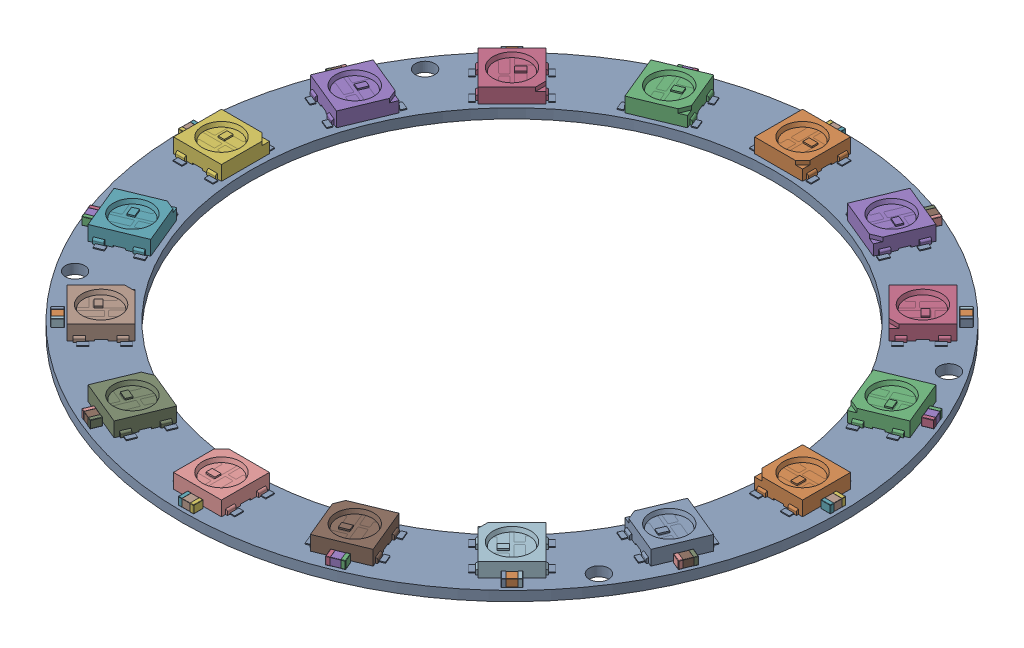
SolidWorks assembly ledRing, configuration Standard. Lengths in mm.
Overall size (68 2.5 68).
33 component instances, 3 part files, 6 mates.
Components (placement in the parent):
- LedRing-1: LedRing [Standard] at origin size (68 1.1 68)
- neopixel-1: neopixel [Standard] at (0 1 -29.975) x (0 0 1) z (0 1 0) size (4.95 5.35 1.7)
- neopixel-2: neopixel [Standard] at (-11.4709 1 -27.6933) x (0.382683 0 0.92388) z (0 1 0) size (4.95 5.35 1.7)
- neopixel-3: neopixel [Standard] at (-21.1955 1 -21.1955) x (0.707107 0 0.707107) z (0 1 0) size (4.95 5.35 1.7)
- neopixel-4: neopixel [Standard] at (-27.6933 1 -11.4709) x (0.92388 0 0.382683) z (0 1 0) size (4.95 5.35 1.7)
- neopixel-5: neopixel [Standard] at (-29.975 1 0) x (1 0 0) z (0 1 0) size (4.95 5.35 1.7)
- neopixel-6: neopixel [Standard] at (-27.6933 1 11.4709) x (0.92388 0 -0.382683) z (0 1 0) size (4.95 5.35 1.7)
- neopixel-7: neopixel [Standard] at (-21.1955 1 21.1955) x (0.707107 0 -0.707107) z (0 1 0) size (4.95 5.35 1.7)
- neopixel-8: neopixel [Standard] at (-11.4709 1 27.6933) x (0.382683 0 -0.92388) z (0 1 0) size (4.95 5.35 1.7)
- neopixel-9: neopixel [Standard] at (0 1 29.975) x (0 0 -1) z (0 1 0) size (4.95 5.35 1.7)
- neopixel-10: neopixel [Standard] at (11.4709 1 27.6933) x (-0.382683 0 -0.92388) z (0 1 0) size (4.95 5.35 1.7)
- neopixel-11: neopixel [Standard] at (21.1955 1 21.1955) x (-0.707107 0 -0.707107) z (0 1 0) size (4.95 5.35 1.7)
- neopixel-12: neopixel [Standard] at (27.6933 1 11.4709) x (-0.92388 0 -0.382683) z (0 1 0) size (4.95 5.35 1.7)
- neopixel-13: neopixel [Standard] at (29.975 1 0) x (-1 0 0) z (0 1 0) size (4.95 5.35 1.7)
- neopixel-14: neopixel [Standard] at (27.6933 1 -11.4709) x (-0.92388 0 0.382683) z (0 1 0) size (4.95 5.35 1.7)
- neopixel-15: neopixel [Standard] at (21.1955 1 -21.1955) x (-0.707107 0 0.707107) z (0 1 0) size (4.95 5.35 1.7)
- neopixel-16: neopixel [Standard] at (11.4709 1 -27.6933) x (-0.382683 0 0.92388) z (0 1 0) size (4.95 5.35 1.7)
- GRM188R60J226MEA0J-1: GRM188R60J226MEA0J [Standard] at (-33.65 1.4 0) x (0 0 -1) z (0 -1 0) size (1.6 1 0.8)
- GRM188R60J226MEA0J-2: GRM188R60J226MEA0J [Standard] at (-31.0885 1.4 -12.8773) x (0.382683 0 -0.92388) z (0 -1 0) size (1.6 1 0.8)
- GRM188R60J226MEA0J-3: GRM188R60J226MEA0J [Standard] at (-23.7941 1.4 -23.7941) x (0.707107 0 -0.707107) z (0 -1 0) size (1.6 1 0.8)
- GRM188R60J226MEA0J-4: GRM188R60J226MEA0J [Standard] at (-12.8773 1.4 -31.0885) x (0.92388 0 -0.382683) z (0 -1 0) size (1.6 1 0.8)
- GRM188R60J226MEA0J-5: GRM188R60J226MEA0J [Standard] at (0 1.4 -33.65) x (1 0 0) z (0 -1 0) size (1.6 1 0.8)
- GRM188R60J226MEA0J-6: GRM188R60J226MEA0J [Standard] at (12.8773 1.4 -31.0885) x (0.92388 0 0.382683) z (0 -1 0) size (1.6 1 0.8)
- GRM188R60J226MEA0J-7: GRM188R60J226MEA0J [Standard] at (23.7941 1.4 -23.7941) x (0.707107 0 0.707107) z (0 -1 0) size (1.6 1 0.8)
- GRM188R60J226MEA0J-8: GRM188R60J226MEA0J [Standard] at (31.0885 1.4 -12.8773) x (0.382683 0 0.92388) z (0 -1 0) size (1.6 1 0.8)
- GRM188R60J226MEA0J-9: GRM188R60J226MEA0J [Standard] at (33.65 1.4 0) x (0 0 1) z (0 -1 0) size (1.6 1 0.8)
- GRM188R60J226MEA0J-10: GRM188R60J226MEA0J [Standard] at (31.0885 1.4 12.8773) x (-0.382683 0 0.92388) z (0 -1 0) size (1.6 1 0.8)
- GRM188R60J226MEA0J-11: GRM188R60J226MEA0J [Standard] at (23.7941 1.4 23.7941) x (-0.707107 0 0.707107) z (0 -1 0) size (1.6 1 0.8)
- GRM188R60J226MEA0J-12: GRM188R60J226MEA0J [Standard] at (12.8773 1.4 31.0885) x (-0.92388 0 0.382683) z (0 -1 0) size (1.6 1 0.8)
- GRM188R60J226MEA0J-13: GRM188R60J226MEA0J [Standard] at (0 1.4 33.65) x (-1 0 0) z (0 -1 0) size (1.6 1 0.8)
- GRM188R60J226MEA0J-14: GRM188R60J226MEA0J [Standard] at (-12.8773 1.4 31.0885) x (-0.92388 0 -0.382683) z (0 -1 0) size (1.6 1 0.8)
- GRM188R60J226MEA0J-15: GRM188R60J226MEA0J [Standard] at (-23.7941 1.4 23.7941) x (-0.707107 0 -0.707107) z (0 -1 0) size (1.6 1 0.8)
- GRM188R60J226MEA0J-16: GRM188R60J226MEA0J [Standard] at (-31.0885 1.4 12.8773) x (-0.382683 0 -0.92388) z (0 -1 0) size (1.6 1 0.8)
Mates (geometry in assembly coordinates):
- Abstand1: distance = 0.5 mm anti-aligned: plane of neopixel-1 through (-2.475 2.5 -27.5) normal (0 0 1); cylinder of LedRing-1 through (0 1 0) axis (0 -1 0) radius 27
- Breite1: width anti-aligned: plane of neopixel-1 through (2.475 2.5 -27.5) normal (1 0 0); plane of neopixel-1 through (-2.475 2.5 -32.45) normal (-1 0 0); plane of LedRing-1 through (-3.175 1.1 -31.775) normal (-1 0 0); plane of LedRing-1 through (3.175 1.1 -31.775) normal (1 0 0)
- Deckungsgleich1: coincident anti-aligned: plane of LedRing-1 through (0 1 0) normal (0 1 0); plane of neopixel-1 through (0 1 -29.975) normal (0 -1 0)
- Breite2: width anti-aligned: plane of neopixel-5 through (-32.45 2.5 2.475) normal (0 0 1); plane of GRM188R60J226MEA0J-1 through (-27.5 2.5 -2.475) normal (0 0 -1); plane of neopixel-5 through (-32.65 1.8 -0.8) normal (0 0 -1); plane of GRM188R60J226MEA0J-1 through (-32.65 1.8 0.8) normal (0 0 1)
- Deckungsgleich2: coincident anti-aligned: plane of LedRing-1 through (0 1 0) normal (0 1 0); plane of GRM188R60J226MEA0J-1 through (-32.65 1 0.8) normal (0 -1 0)
- Abstand2: distance = 0.2 mm anti-aligned: plane of GRM188R60J226MEA0J-1 through (-32.65 1.4 0) normal (1 0 0); plane of neopixel-5 through (-32.45 2.5 -2.475) normal (-1 0 0)
